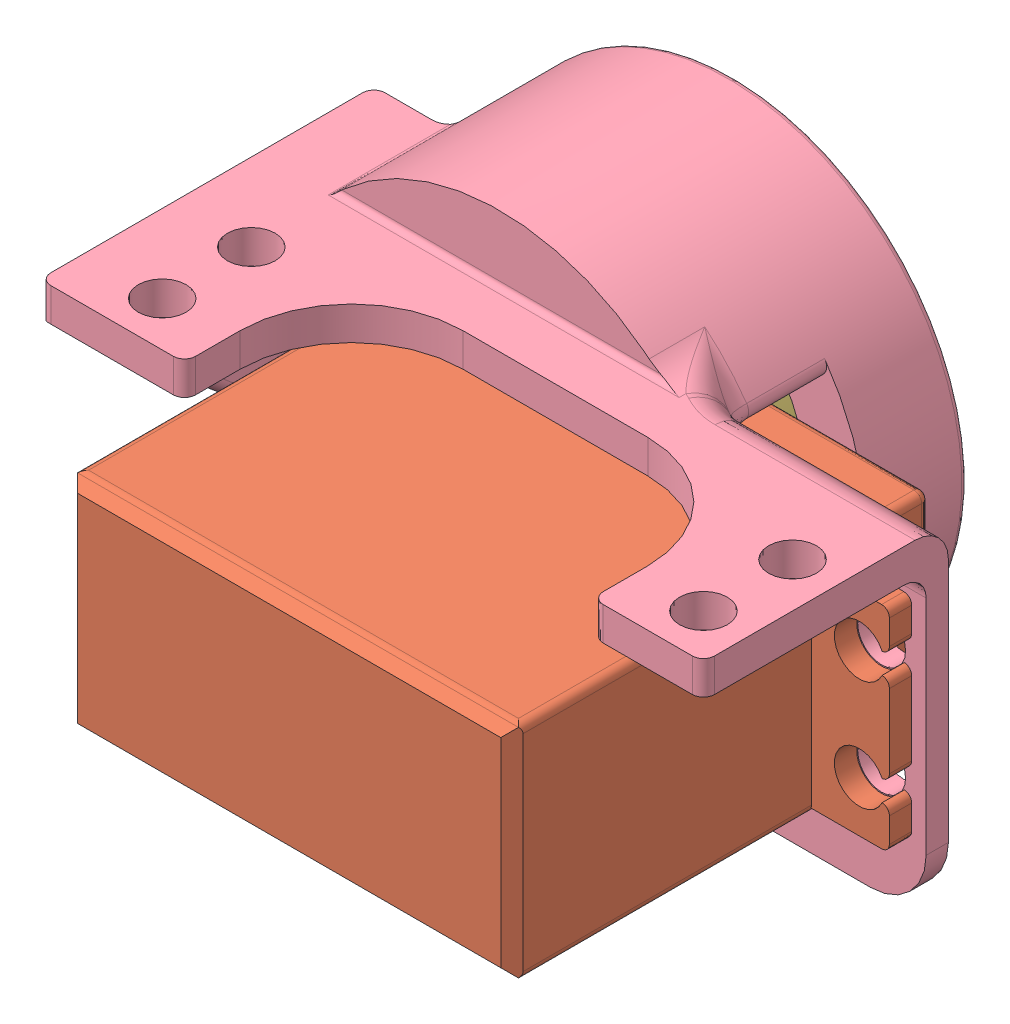
SolidWorks assembly 腿部固定总成, configuration 默认. Lengths in mm.
Overall size (67.6 48.35 50.13).
4 component instances, 4 part files, 7 mates.
Components (placement in the parent):
- 6706一30x37x4轴承-1: 6706一30x37x4轴承 [默认] at (4.3976 -20.383 50.3977) x (-0.923728 -0.383049 0) z (0 0 -1) size (37 37 4)
- MG996R-1: MG996R [默认] at (34.3976 -30.333 96.2977) x (-1 0 0) z (0 -1 0) size (54 43.2 19.9)
- 舵盘-1: 舵盘 [默认] at (4.3976 -20.4396 53.0977) size (20 20 4.5)
- 舵机固定件_轴承_机体部分-1: 舵机固定件_轴承_机体部分 [默认] at (-6.6024 -30.883 65.3977) size (67.6 42 41.23)
Mates (geometry in assembly coordinates):
- 重合3: coincident anti-aligned: plane of MG996R-1 through (4.3976 -20.4396 53.0977) normal (0 0 -1); plane of 舵盘-1 through (4.3976 -20.4396 53.0977) normal (0 0 1)
- 同心9: concentric aligned: circle of MG996R-1; circle of 舵盘-1
- 重合4: coincident anti-aligned: plane of 6706一30x37x4轴承-1 through (4.3976 -20.383 50.3977) normal (0 0 1); plane of 舵机固定件_轴承_机体部分-1 through (-6.6024 -30.883 50.3977) normal (0 0 -1)
- 同心10: concentric aligned: circle of MG996R-1; circle of 舵机固定件_轴承_机体部分-1
- 同心11: concentric aligned: circle of MG996R-1; circle of 舵机固定件_轴承_机体部分-1
- 重合6: coincident anti-aligned: plane of MG996R-1 through (34.3976 -30.333 67.3977) normal (0 0 -1); plane of 舵机固定件_轴承_机体部分-1 through (-6.6024 -30.883 67.3977) normal (0 0 1)
- 同心12: concentric aligned: circle of 6706一30x37x4轴承-1; circle of 舵机固定件_轴承_机体部分-1
